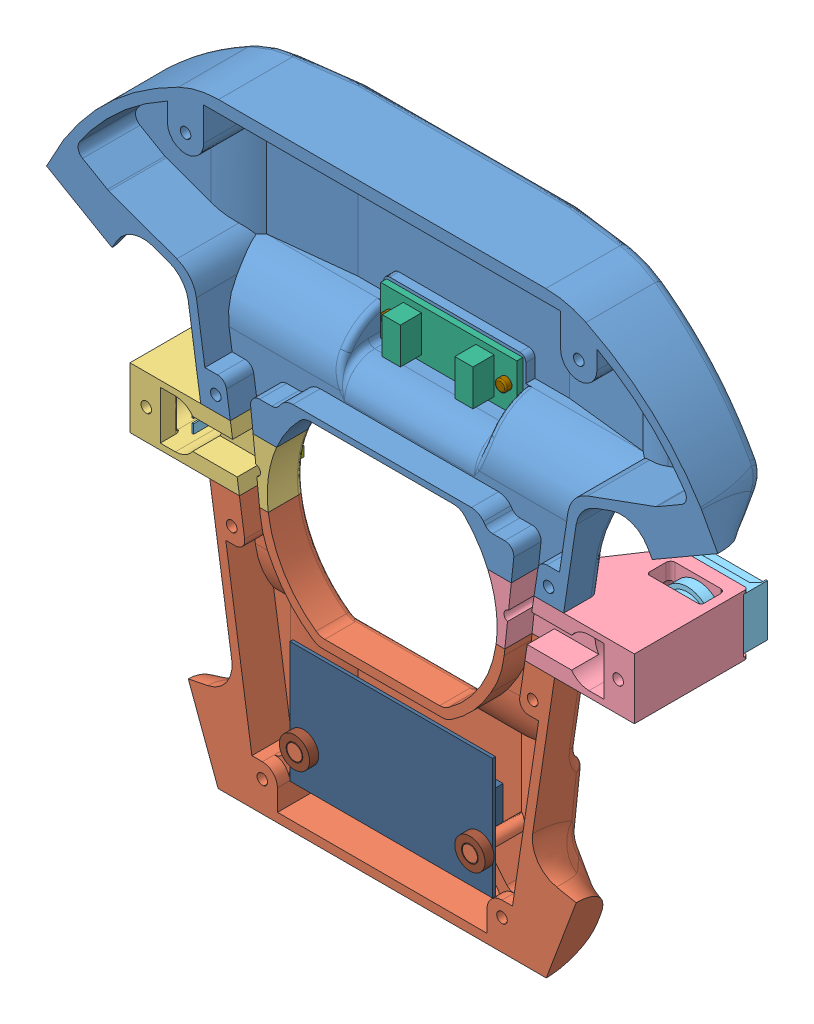
SolidWorks assembly RF019 SWB&PSM, configuration ﾃﾞﾌｫﾙﾄ. Lengths in mm.
Overall size (250 250 58.49).
26 component instances, 11 part files, 71 mates.
Components (placement in the parent):
- RF019 SWB kai B1-1: RF019 SWB kai B1 [ﾃﾞﾌｫﾙﾄ] at (-53.2958 -19.4307 279.1952) size (250 250 58.49)
- RF019 SWB kai B3-1: RF019 SWB kai B3 [ﾃﾞﾌｫﾙﾄ] at (-53.2958 -19.4307 279.1952) size (250 250 48.2)
- RF019 SWB PSMB2L kai-1: RF019 SWB PSMB2L kai [ﾃﾞﾌｫﾙﾄ] at (-53.2958 -19.4307 279.1952) size (250 250 48.15)
- RF019 SWB PSMB2R kai-1: RF019 SWB PSMB2R kai [ﾃﾞﾌｫﾙﾄ] at (-53.2958 -19.4307 279.1952) size (250 250 48.15)
- RF018 IDEC Switch-1: RF018 IDEC Switch [ﾃﾞﾌｫﾙﾄ] at (-124.6708 -14.4307 243.1952) x (0 1 0) z (0 0 -1) size (17 23 38.5)
- RF018 IDEC Switch-2: RF018 IDEC Switch [ﾃﾞﾌｫﾙﾄ] at (18.0792 -14.4307 243.1952) x (0 -1 0) z (0 0 -1) size (17 23 38.5)
- RF019 CC-1: RF019 CC [ﾃﾞﾌｫﾙﾄ] at (-53.2958 30.039 257.1952) x (-1 0 0) z (0 0 -1) size (45 16 22)
- M3 Nat-1: M3 Nat [ﾃﾞﾌｫﾙﾄ] at (-3.5573 -34.4307 268.7952) x (0.998944 0.04595 0) z (0 0 1) size (5.64 6.34 2.4)
- M3 Nat-2: M3 Nat [ﾃﾞﾌｫﾙﾄ] at (-13.6813 -101.7767 261.7952) x (0.998944 0.04595 0) z (0 0 1) size (5.64 6.34 2.4)
- M3 Nat-3: M3 Nat [ﾃﾞﾌｫﾙﾄ] at (11.7042 70.5693 254.7952) x (0.998944 0.04595 0) z (0 0 1) size (5.64 6.34 2.4)
- M3 Nat-4: M3 Nat [ﾃﾞﾌｫﾙﾄ] at (-103.0343 -34.4307 268.7952) x (0.998944 0.04595 0) z (0 0 1) size (5.64 6.34 2.4)
- M3 Nat-5: M3 Nat [ﾃﾞﾌｫﾙﾄ] at (-108.2958 0.5693 268.7952) x (0.998944 0.04595 0) z (0 0 1) size (5.64 6.34 2.4)
- M3 Nat-6: M3 Nat [ﾃﾞﾌｫﾙﾄ] at (1.7042 0.5693 268.7952) x (0.998944 0.04595 0) z (0 0 1) size (5.64 6.34 2.4)
- M3 Nat-7: M3 Nat [ﾃﾞﾌｫﾙﾄ] at (-118.2958 70.5693 254.7952) x (0.998944 0.04595 0) z (0 0 1) size (5.64 6.34 2.4)
- M3 Nat-8: M3 Nat [ﾃﾞﾌｫﾙﾄ] at (-92.9103 -101.7767 261.7952) x (0.998944 0.04595 0) z (0 0 1) size (5.64 6.34 2.4)
- M3 Nat-9: M3 Nat [ﾃﾞﾌｫﾙﾄ] at (-11.2958 -14.4307 265.7952) x (0.459678 0.888086 0) z (0 0 1) size (5.64 6.34 2.4)
- M3 Nat-10: M3 Nat [ﾃﾞﾌｫﾙﾄ] at (-95.2958 -14.4307 265.7952) x (0.459678 0.888086 0) z (0 0 1) size (5.64 6.34 2.4)
- M3 Nat-11: M3 Nat [ﾃﾞﾌｫﾙﾄ] at (24.7042 -14.4307 273.7952) x (0.998944 0.04595 0) z (0 0 1) size (5.64 6.34 2.4)
- M3 Nat-12: M3 Nat [ﾃﾞﾌｫﾙﾄ] at (-131.2958 -14.4307 273.7952) x (0.998944 0.04595 0) z (0 0 1) size (5.64 6.34 2.4)
- M2 Nat-1: M2 Nat [ﾃﾞﾌｫﾙﾄ] at (-72.2958 30.039 250.5952) x (0.998944 0.04595 0) z (0 0 1) size (4.1 4.61 1.6)
- M2 Nat-2: M2 Nat [ﾃﾞﾌｫﾙﾄ] at (-34.2958 30.039 252.1952) x (0.998944 -0.04595 0) z (0 0 -1) size (4.1 4.61 1.6)
- M2 8 Bolt-1: M2 8 Bolt [ﾃﾞﾌｫﾙﾄ] at (-34.2958 30.039 259.1952) x (-0.923728 -0.383049 0) z (0 0 -1) size (3.8 3.8 10)
- M2 8 Bolt-2: M2 8 Bolt [ﾃﾞﾌｫﾙﾄ] at (-72.2958 30.039 259.1952) x (-0.923728 -0.383049 0) z (0 0 -1) size (3.8 3.8 10)
- RF019 SC kai-1: RF019 SC kai [ﾃﾞﾌｫﾙﾄ] at (-53.2958 -80.7767 276.1952) x (-1 0 0) z (0 0 -1) size (67 40 14.5)
- RF018 Spacer for Shifter Circle[Φ5 3]-1: RF018 Spacer for Shifter Circle[Φ5 3] [ﾃﾞﾌｫﾙﾄ] at (-82.2958 -88.7767 276.1952) x (0.815194 -0.579188 0) z (0 0 1) size (10 10 2)
- RF018 Spacer for Shifter Circle[Φ5 3]-2: RF018 Spacer for Shifter Circle[Φ5 3] [ﾃﾞﾌｫﾙﾄ] at (-24.2958 -88.7767 276.1952) x (0.906897 -0.421352 0) z (0 0 1) size (10 10 2)
Mates (geometry in assembly coordinates):
- 一致1: coincident aligned: plane of RF019 SWB kai B1-1 through (-53.2958 -19.4307 279.1952) normal (0 0 1); plane of RF019 SWB PSMB2L kai-1 through (-53.2958 -19.4307 279.1952) normal (0 0 1)
- 一致2: coincident aligned: plane of RF019 SWB kai B1-1 through (-53.2958 -19.4307 279.1952) normal (0 0 1); plane of RF019 SWB PSMB2R kai-1 through (-53.2958 -19.4307 279.1952) normal (0 0 1)
- 一致3: coincident aligned: plane of RF019 SWB kai B1-1 through (-53.2958 -19.4307 279.1952) normal (0 0 1); plane of RF019 SWB kai B3-1 through (-53.2958 -19.4307 279.1952) normal (0 0 1)
- 一致4: coincident anti-aligned: plane of RF019 SWB kai B1-1 through (-113.2958 -4.4307 229.1952) normal (0 -1 0); plane of RF019 SWB PSMB2L kai-1 through (-127.9318 -4.4307 229.1952) normal (0 1 0)
- 一致5: coincident anti-aligned: plane of RF019 SWB kai B1-1 through (-113.2958 -4.4307 229.1952) normal (0 -1 0); plane of RF019 SWB PSMB2R kai-1 through (21.3402 -4.4307 229.1952) normal (0 1 0)
- 一致6: coincident anti-aligned: plane of RF019 SWB kai B3-1 through (38.0955 -24.4307 229.1952) normal (0 1 0); plane of RF019 SWB PSMB2R kai-1 through (3.6977 -24.4307 229.1952) normal (0 -1 0)
- 同心円1: concentric aligned: cylinder of RF019 SWB kai B1-1 through (-53.2958 -19.4307 267.1952) axis (0 0 1) radius 38; cylinder of RF019 SWB PSMB2L kai-1 through (-53.2958 -19.4307 267.1952) axis (0 0 1) radius 38
- 同心円2: concentric aligned: cylinder of RF019 SWB kai B1-1 through (-53.2958 -19.4307 267.1952) axis (0 0 1) radius 38; cylinder of RF019 SWB PSMB2R kai-1 through (-53.2958 -19.4307 267.1952) axis (0 0 1) radius 38
- 同心円3: concentric aligned: cylinder of RF019 SWB kai B1-1 through (-53.2958 -19.4307 267.1952) axis (0 0 1) radius 38; cylinder of RF019 SWB kai B3-1 through (-53.2958 -19.4307 267.1952) axis (0 0 1) radius 38
- 同心円4: concentric aligned: cylinder of RF019 SWB PSMB2L kai-1 through (-124.6708 -14.4307 253.1952) axis (0 0 -1) radius 8.5; cylinder of RF018 IDEC Switch-1 through (-124.6708 -14.4307 265.1952) axis (0 0 -1) radius 7
- 一致7: coincident anti-aligned: plane of RF019 SWB PSMB2L kai-1 through (-136.6708 -24.4307 243.1952) normal (0 0 -1); plane of RF018 IDEC Switch-1 through (-124.6708 -14.4307 243.1952) normal (0 0 1)
- 平行1: parallel aligned: plane of RF019 SWB PSMB2L kai-1 through (-136.6708 -23.4307 241.6952) normal (0 1 0); plane of RF018 IDEC Switch-1 through (-113.1708 -5.9307 234.6952) normal (0 1 0)
- 同心円5: concentric aligned: cylinder of RF019 SWB PSMB2R kai-1 through (18.0792 -14.4307 253.1952) axis (0 0 -1) radius 8.5; cylinder of RF018 IDEC Switch-2 through (18.0792 -14.4307 265.1952) axis (0 0 -1) radius 7
- 一致9: coincident anti-aligned: plane of RF019 SWB PSMB2R kai-1 through (30.0792 -24.4307 243.1952) normal (0 0 -1); plane of RF018 IDEC Switch-2 through (18.0792 -14.4307 243.1952) normal (0 0 1)
- 平行2: parallel anti-aligned: plane of RF019 SWB PSMB2R kai-1 through (30.0792 -23.4307 241.6952) normal (0 1 0); plane of RF018 IDEC Switch-2 through (6.5792 -22.9307 234.6952) normal (0 -1 0)
- 同心円6: concentric aligned: cylinder of RF019 SWB kai B1-1 through (-34.2958 30.039 279.2452) axis (0 0 -1) radius 1.2; cylinder of RF019 CC-1 through (-34.2958 30.039 257.1952) axis (0 0 -1) radius 1.2
- 同心円7: concentric aligned: cylinder of RF019 SWB kai B1-1 through (-72.2958 30.039 279.2452) axis (0 0 -1) radius 1.2; cylinder of RF019 CC-1 through (-72.2958 30.039 257.1952) axis (0 0 -1) radius 1.2
- 一致11: coincident anti-aligned: plane of RF019 SWB kai B1-1 through (-53.2958 -19.4307 255.1952) normal (0 0 1); plane of RF019 CC-1 through (-53.2958 30.039 255.1952) normal (0 0 -1)
- 同心円8: concentric anti-aligned: cylinder of RF019 SWB kai B1-1 through (11.7042 70.5693 229.1952) axis (0 0 1) radius 1.75; cylinder of M3 Nat-3 through (11.7042 70.5693 257.1952) axis (0 0 -1) radius 1.5
- 一致12: coincident anti-aligned: plane of RF019 SWB kai B1-1 through (-53.2958 -19.4307 257.1952) normal (0 0 -1); plane of M3 Nat-3 through (11.7042 70.5693 257.1952) normal (0 0 1)
- 平行3: parallel anti-aligned: plane of RF019 SWB kai B1-1 through (14.5792 72.2291 257.1952) normal (-1 0 0); plane of M3 Nat-3 through (14.4542 68.9815 257.1952) normal (1 0 0)
- 同心円9: concentric anti-aligned: cylinder of RF019 SWB kai B1-1 through (1.7042 0.5693 229.1952) axis (0 0 1) radius 1.75; cylinder of M3 Nat-6 through (1.7042 0.5693 271.1952) axis (0 0 -1) radius 1.5
- 一致14: coincident anti-aligned: plane of RF019 SWB kai B1-1 through (-53.2958 -19.4307 271.1952) normal (0 0 -1); plane of M3 Nat-6 through (1.7042 0.5693 271.1952) normal (0 0 1)
- 平行4: parallel anti-aligned: plane of RF019 SWB kai B1-1 through (4.5792 2.2291 271.1952) normal (-1 0 0); plane of M3 Nat-6 through (4.4542 -1.0185 271.1952) normal (1 0 0)
- 同心円10: concentric anti-aligned: cylinder of RF019 SWB kai B3-1 through (-3.5573 -34.4307 229.1952) axis (0 0 1) radius 1.75; cylinder of M3 Nat-1 through (-3.5573 -34.4307 271.1952) axis (0 0 -1) radius 1.5
- 一致16: coincident anti-aligned: plane of RF019 SWB kai B3-1 through (-53.2958 -19.4307 271.1952) normal (0 0 -1); plane of M3 Nat-1 through (-3.5573 -34.4307 271.1952) normal (0 0 1)
- 平行5: parallel anti-aligned: plane of RF019 SWB kai B3-1 through (-0.6823 -32.7709 271.1952) normal (-1 0 0); plane of M3 Nat-1 through (-0.8073 -36.0185 271.1952) normal (1 0 0)
- 同心円11: concentric anti-aligned: cylinder of RF019 SWB kai B3-1 through (-13.6813 -101.7767 229.1952) axis (0 0 1) radius 1.75; cylinder of M3 Nat-2 through (-13.6813 -101.7767 264.1952) axis (0 0 -1) radius 1.5
- 一致18: coincident anti-aligned: plane of RF019 SWB kai B3-1 through (-53.2958 -19.4307 264.1952) normal (0 0 -1); plane of M3 Nat-2 through (-13.6813 -101.7767 264.1952) normal (0 0 1)
- 平行6: parallel anti-aligned: plane of RF019 SWB kai B3-1 through (-10.8063 -100.1169 264.1952) normal (-1 0 0); plane of M3 Nat-2 through (-10.9313 -103.3645 264.1952) normal (1 0 0)
- 同心円12: concentric anti-aligned: cylinder of RF019 SWB kai B1-1 through (-118.2958 70.5693 229.1952) axis (0 0 1) radius 1.75; cylinder of M3 Nat-7 through (-118.2958 70.5693 257.1952) axis (0 0 -1) radius 1.5
- 一致20: coincident anti-aligned: plane of RF019 SWB kai B1-1 through (-53.2958 -19.4307 257.1952) normal (0 0 -1); plane of M3 Nat-7 through (-118.2958 70.5693 257.1952) normal (0 0 1)
- 平行7: parallel anti-aligned: plane of RF019 SWB kai B1-1 through (-121.1708 68.9094 257.1952) normal (1 0 0); plane of M3 Nat-7 through (-121.0458 72.157 257.1952) normal (-1 0 0)
- 同心円13: concentric anti-aligned: cylinder of RF019 SWB kai B1-1 through (-108.2958 0.5693 229.1952) axis (0 0 1) radius 1.75; cylinder of M3 Nat-5 through (-108.2958 0.5693 271.1952) axis (0 0 -1) radius 1.5
- 一致22: coincident anti-aligned: plane of RF019 SWB kai B1-1 through (-53.2958 -19.4307 271.1952) normal (0 0 -1); plane of M3 Nat-5 through (-108.2958 0.5693 271.1952) normal (0 0 1)
- 平行8: parallel anti-aligned: plane of RF019 SWB kai B1-1 through (-111.1708 2.2291 271.1952) normal (1 0 0); plane of M3 Nat-5 through (-111.0458 2.157 271.1952) normal (-1 0 0)
- 同心円14: concentric anti-aligned: cylinder of RF019 SWB kai B3-1 through (-103.0343 -34.4307 229.1952) axis (0 0 1) radius 1.75; cylinder of M3 Nat-4 through (-103.0343 -34.4307 271.1952) axis (0 0 -1) radius 1.5
- 一致24: coincident anti-aligned: plane of RF019 SWB kai B3-1 through (-53.2958 -19.4307 271.1952) normal (0 0 -1); plane of M3 Nat-4 through (-103.0343 -34.4307 271.1952) normal (0 0 1)
- 平行9: parallel anti-aligned: plane of RF019 SWB kai B3-1 through (-105.9093 -32.7709 271.1952) normal (1 0 0); plane of M3 Nat-4 through (-105.7843 -32.843 271.1952) normal (-1 0 0)
- 同心円15: concentric anti-aligned: cylinder of RF019 SWB kai B3-1 through (-92.9103 -101.7767 229.1952) axis (0 0 1) radius 1.75; cylinder of M3 Nat-8 through (-92.9103 -101.7767 264.1952) axis (0 0 -1) radius 1.5
- 一致26: coincident anti-aligned: plane of RF019 SWB kai B3-1 through (-53.2958 -19.4307 264.1952) normal (0 0 -1); plane of M3 Nat-8 through (-92.9103 -101.7767 264.1952) normal (0 0 1)
- 平行10: parallel anti-aligned: plane of RF019 SWB kai B3-1 through (-95.7853 -103.4366 264.1952) normal (1 0 0); plane of M3 Nat-8 through (-95.6603 -100.189 264.1952) normal (-1 0 0)
- 同心円16: concentric anti-aligned: cylinder of RF019 SWB PSMB2L kai-1 through (-95.2958 -14.4307 267.1952) axis (0 0 1) radius 1.75; cylinder of M3 Nat-10 through (-95.2958 -14.4307 268.1952) axis (0 0 -1) radius 1.5
- 一致28: coincident anti-aligned: plane of RF019 SWB PSMB2L kai-1 through (-53.2958 -19.4307 268.1952) normal (0 0 -1); plane of M3 Nat-10 through (-95.2958 -14.4307 268.1952) normal (0 0 1)
- 平行11: parallel anti-aligned: plane of RF019 SWB PSMB2L kai-1 through (-92.4208 -12.7709 268.1952) normal (-1 0 0); plane of M3 Nat-10 through (-92.5458 -16.0185 268.1952) normal (1 0 0)
- 同心円17: concentric anti-aligned: cylinder of RF019 SWB PSMB2R kai-1 through (-11.2958 -14.4307 267.1952) axis (0 0 1) radius 1.75; cylinder of M3 Nat-9 through (-11.2958 -14.4307 268.1952) axis (0 0 -1) radius 1.5
- 一致30: coincident anti-aligned: plane of RF019 SWB PSMB2R kai-1 through (-53.2958 -19.4307 268.1952) normal (0 0 -1); plane of M3 Nat-9 through (-11.2958 -14.4307 268.1952) normal (0 0 1)
- 平行12: parallel anti-aligned: plane of RF019 SWB PSMB2R kai-1 through (-14.1708 -12.7709 268.1952) normal (1 0 0); plane of M3 Nat-9 through (-14.0458 -12.843 268.1952) normal (-1 0 0)
- 同心円18: concentric anti-aligned: cylinder of RF019 SWB PSMB2R kai-1 through (24.7042 -14.4307 276.1952) axis (0 0 1) radius 1.75; cylinder of M3 Nat-11 through (24.7042 -14.4307 276.1952) axis (0 0 -1) radius 1.5
- 一致32: coincident anti-aligned: plane of RF019 SWB PSMB2R kai-1 through (-53.2958 -19.4307 276.1952) normal (0 0 -1); plane of M3 Nat-11 through (24.7042 -14.4307 276.1952) normal (0 0 1)
- 同心円19: concentric anti-aligned: cylinder of RF019 SWB PSMB2L kai-1 through (-131.2958 -14.4307 276.1952) axis (0 0 1) radius 1.75; cylinder of M3 Nat-12 through (-131.2958 -14.4307 276.1952) axis (0 0 -1) radius 1.5
- 一致33: coincident anti-aligned: plane of RF019 SWB PSMB2L kai-1 through (-53.2958 -19.4307 276.1952) normal (0 0 -1); plane of M3 Nat-12 through (-131.2958 -14.4307 276.1952) normal (0 0 1)
- 平行13: parallel anti-aligned: plane of RF019 SWB PSMB2L kai-1 through (-131.2958 -11.111 276.1952) normal (-0.5 -0.866025 0); plane of M3 Nat-12 through (-128.5458 -12.843 276.1952) normal (0.5 0.866025 0)
- 平行14: parallel anti-aligned: plane of RF019 SWB PSMB2R kai-1 through (27.5792 -12.7709 276.1952) normal (-0.5 -0.866025 0); plane of M3 Nat-11 through (27.4542 -12.843 276.1952) normal (0.5 0.866025 0)
- 同心円20: concentric aligned: cylinder of RF019 SWB kai B1-1 through (-72.2958 30.039 279.2452) axis (0 0 -1) radius 1.2; cylinder of M2 Nat-1 through (-72.2958 30.039 252.1952) axis (0 0 -1) radius 1
- 一致36: coincident anti-aligned: plane of RF019 SWB kai B1-1 through (-53.2958 -19.4307 252.1952) normal (0 0 -1); plane of M2 Nat-1 through (-72.2958 30.039 252.1952) normal (0 0 1)
- 平行15: parallel anti-aligned: plane of RF019 SWB kai B1-1 through (-74.4458 28.7977 252.1952) normal (1 0 0); plane of M2 Nat-1 through (-74.2958 31.1937 252.1952) normal (-1 0 0)
- 同心円21: concentric anti-aligned: cylinder of RF019 SWB kai B1-1 through (-34.2958 30.039 279.2452) axis (0 0 -1) radius 1.2; cylinder of M2 Nat-2 through (-34.2958 30.039 250.5952) axis (0 0 1) radius 1
- 一致38: coincident anti-aligned: plane of RF019 SWB kai B1-1 through (-53.2958 -19.4307 252.1952) normal (0 0 -1); plane of M2 Nat-2 through (-34.2958 30.039 252.1952) normal (0 0 1)
- 平行16: parallel anti-aligned: plane of RF019 SWB kai B1-1 through (-32.1458 28.7977 252.1952) normal (-0.5 0.866025 0); plane of M2 Nat-2 through (-32.2958 28.8843 250.5952) normal (0.5 -0.866025 0)
- 同心円22: concentric anti-aligned: cylinder of RF019 SWB kai B1-1 through (-34.2958 30.039 279.2452) axis (0 0 -1) radius 1.2; cylinder of M2 8 Bolt-1 through (-34.2958 30.039 249.1952) axis (0 0 1) radius 1
- 一致40: coincident anti-aligned: plane of RF019 CC-1 through (-53.2958 30.039 257.1952) normal (0 0 1); plane of M2 8 Bolt-1 through (-34.2958 30.039 257.1952) normal (0 0 -1)
- 同心円23: concentric anti-aligned: cylinder of RF019 SWB kai B1-1 through (-72.2958 30.039 279.2452) axis (0 0 -1) radius 1.2; cylinder of M2 8 Bolt-2 through (-72.2958 30.039 249.1952) axis (0 0 1) radius 1
- 一致41: coincident anti-aligned: plane of RF019 CC-1 through (-53.2958 30.039 257.1952) normal (0 0 1); plane of M2 8 Bolt-2 through (-72.2958 30.039 257.1952) normal (0 0 -1)
- 同心円24: concentric anti-aligned: cylinder of RF019 SWB kai B3-1 through (-24.2958 -88.7767 260.1952) axis (0 0 1) radius 2.5; cylinder of RF019 SC kai-1 through (-24.2958 -88.7767 280.1952) axis (0 0 -1) radius 2.75
- 同心円27: concentric anti-aligned: cylinder of RF019 SWB kai B3-1 through (-82.2958 -88.7767 260.1952) axis (0 0 1) radius 2.5; cylinder of RF019 SC kai-1 through (-82.2958 -88.7767 280.1952) axis (0 0 -1) radius 2.75
- 一致42: coincident anti-aligned: plane of RF019 SWB kai B3-1 through (-92.9103 -101.7767 275.1952) normal (0 0 1); plane of RF019 SC kai-1 through (-53.2958 -80.7767 275.1952) normal (0 0 -1)
- 同心円28: concentric anti-aligned: cylinder of RF019 SWB kai B3-1 through (-82.2958 -88.7767 260.1952) axis (0 0 1) radius 2.5; cylinder of RF018 Spacer for Shifter Circle[Φ5 3]-1 through (-82.2958 -88.7767 278.1952) axis (0 0 -1) radius 3.25
- 一致43: coincident anti-aligned: plane of RF019 SC kai-1 through (-53.2958 -80.7767 276.1952) normal (0 0 1); plane of RF018 Spacer for Shifter Circle[Φ5 3]-1 through (-82.2958 -88.7767 276.1952) normal (0 0 -1)
- 同心円29: concentric anti-aligned: cylinder of RF019 SWB kai B3-1 through (-24.2958 -88.7767 260.1952) axis (0 0 1) radius 2.5; cylinder of RF018 Spacer for Shifter Circle[Φ5 3]-2 through (-24.2958 -88.7767 278.1952) axis (0 0 -1) radius 3.25
- 一致44: coincident anti-aligned: plane of RF019 SC kai-1 through (-53.2958 -80.7767 276.1952) normal (0 0 1); plane of RF018 Spacer for Shifter Circle[Φ5 3]-2 through (-24.2958 -88.7767 276.1952) normal (0 0 -1)
